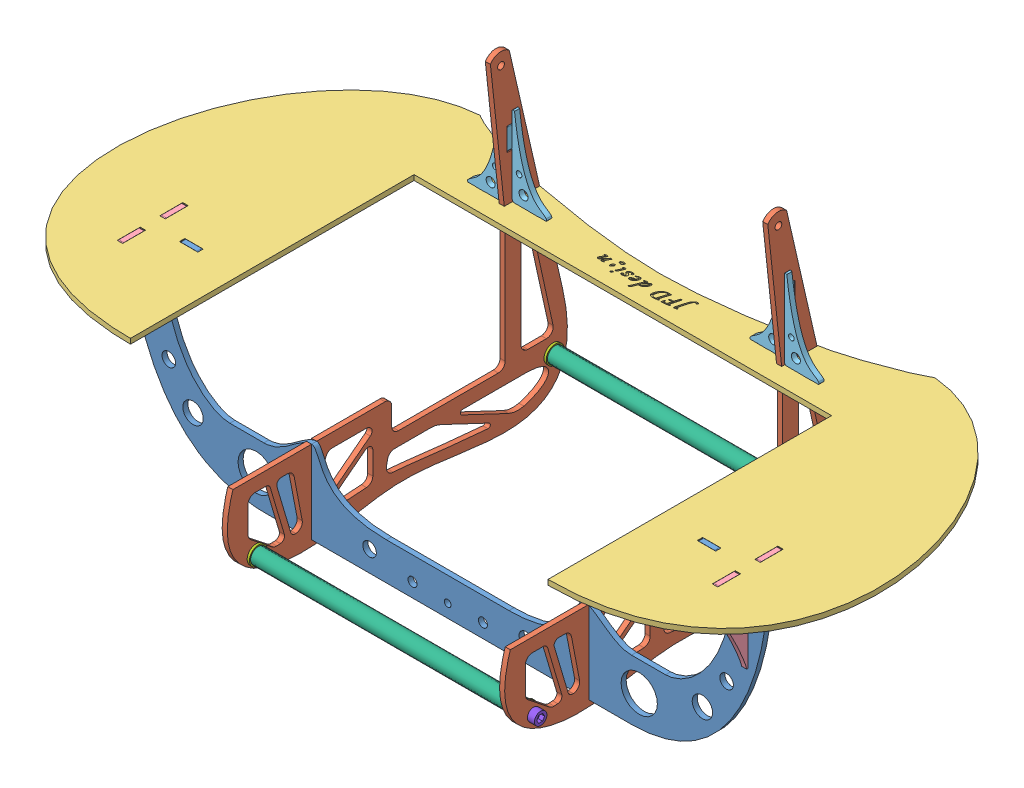
SolidWorks assembly PUPITRE2_ASM_final, configuration Default. Lengths in mm.
Overall size (343.04 155.74 164.22).
28 component instances, 8 part files, 45 mates.
Components (placement in the parent):
- TRAVERSE-1: TRAVERSE [Default] at (24.2232 -32.0952 -9.6228) size (312.1 84.77 2.25)
- FLANGE-1: FLANGE [Default] at (136.4732 -2.886 -18.3978) x (-1 0 0) z (0 0 -1) size (2.25 155.74 160.35)
- FLANGE-2: FLANGE [Default] at (14.2232 -2.886 -18.3978) x (-1 0 0) z (0 0 -1) size (2.25 155.74 160.35)
- PLATINE-2: PLATINE [Default] at (24.2232 33.9548 -84.5577) x (-1 0 0) z (0 0 -1) size (343.04 2.25 162.21)
- WEDGE1-1: WEDGE1 [Default] at (156.4732 21.4548 -8.4978) x (-1 0 0) z (0 0 -1) size (2.25 38.02 66.03)
- WEDGE1-2: WEDGE1 [Default] at (-105.7768 21.4548 -8.4978) x (-1 0 0) z (0 0 -1) size (2.25 38.02 66.03)
- WEDGE2-1: WEDGE2 [Default] at (-38.0268 36.2048 -95.8195) size (17.46 37.46 2.25)
- WEDGE2-2: WEDGE2 [Default] at (-35.7768 36.2048 -95.8195) x (-1 0 0) z (0 0 -1) size (17.46 37.46 2.25)
- WEDGE2-3: WEDGE2 [Default] at (84.2232 36.2048 -98.0695) size (17.46 37.46 2.25)
- WEDGE2-4: WEDGE2 [Default] at (86.4732 36.2048 -93.5695) x (-1 0 0) z (0 0 -1) size (17.46 37.46 2.25)
- STIFFNER-1: STIFFNER [Default] at (17.5863 -42.7957 21.3978) size (120 8 8)
  - STIFFNER-1: STIFFNER [Default] at (7.6369 0.9201 -4.3911) size (118 7 7)
  - GLUED_NUT-1: GLUED_NUT [Default] at (-53.3631 0.9201 -4.3911) x (0 -1 0) z (0 0 1) size (8 5 8)
  - GLUED_NUT-2: GLUED_NUT [Default] at (66.6369 0.9201 -4.3911) x (0 1 0) z (0 0 1) size (8 5 8)
- STIFFNER-2: STIFFNER [Default] at (17.5863 28.8847 -94.3222) size (120 8 8)
  - STIFFNER-1: STIFFNER [Default] at (7.6369 0.9201 -4.3911) size (118 7 7)
  - GLUED_NUT-1: GLUED_NUT [Default] at (-53.3631 0.9201 -4.3911) x (0 -1 0) z (0 0 1) size (8 5 8)
  - GLUED_NUT-2: GLUED_NUT [Default] at (66.6369 0.9201 -4.3911) x (0 1 0) z (0 0 1) size (8 5 8)
- STIFFNER-3: STIFFNER [Default] at (17.5863 -31.5278 -109.4197) size (120 8 8)
  - STIFFNER-1: STIFFNER [Default] at (7.6369 0.9201 -4.3911) size (118 7 7)
  - GLUED_NUT-1: GLUED_NUT [Default] at (-53.3631 0.9201 -4.3911) x (0 -1 0) z (0 0 1) size (8 5 8)
  - GLUED_NUT-2: GLUED_NUT [Default] at (66.6369 0.9201 -4.3911) x (0 1 0) z (0 0 1) size (8 5 8)
- M3_HEX_BOLT-1: M3_HEX_BOLT [Default] at (89.5732 -41.8756 17.0067) x (0 1 0) z (0 0 1) size (5.5 13.1 5.5)
- M3_HEX_BOLT-2: M3_HEX_BOLT [Default] at (-41.1268 -30.6077 -113.8109) x (0 -1 0) z (0 0 1) size (5.5 13.1 5.5)
- M3_HEX_BOLT-3: M3_HEX_BOLT [Default] at (89.5732 -30.6077 -113.8109) x (0 -0.381849 0.924225) z (0 -0.924225 -0.381849) size (5.5 13.1 5.5)
- M3_HEX_BOLT-4: M3_HEX_BOLT [Default] at (89.5732 29.8048 -98.7133) x (0 1 0) z (0 0 1) size (5.5 13.1 5.5)
- M3_HEX_BOLT-5: M3_HEX_BOLT [Default] at (-41.1268 29.8048 -98.7133) x (0 -1 0) z (0 0 1) size (5.5 13.1 5.5)
- M3_HEX_BOLT-6: M3_HEX_BOLT [Default] at (-41.1268 -41.8756 17.0067) x (0 -1 0) z (0 0 1) size (5.5 13.1 5.5)
Mates (geometry in assembly coordinates):
- Coincident1: coincident anti-aligned: plane of TRAVERSE-1 through (84.2232 -30.0952 -7.3728) normal (0 -1 0); plane of FLANGE-1 through (84.2232 -30.0952 -7.3728) normal (0 1 0)
- Coincident2: coincident anti-aligned: plane of TRAVERSE-1 through (-35.7768 -30.0952 -7.3728) normal (0 -1 0); plane of FLANGE-2 through (-38.0268 -30.0952 -7.3728) normal (0 1 0)
- Coincident4: coincident anti-aligned: plane of TRAVERSE-1 through (150.9033 -21.8485 -9.6228) normal (0 0 -1); plane of FLANGE-2 through (-38.0268 -12.0952 -9.6228) normal (0 0 1)
- Coincident6: coincident anti-aligned: plane of TRAVERSE-1 through (84.2232 -30.0952 -7.3728) normal (1 0 0); plane of FLANGE-1 through (84.2232 -46.0994 -49.779) normal (-1 0 0)
- Coincident7: coincident anti-aligned: plane of TRAVERSE-1 through (150.9033 -21.8485 -7.3728) normal (0 0 1); plane of FLANGE-1 through (84.2232 -12.0952 -7.3728) normal (0 0 -1)
- Coincident17: coincident anti-aligned: plane of TRAVERSE-1 through (-38.0268 -30.0952 -7.3728) normal (1 0 0); plane of FLANGE-2 through (-38.0268 -46.0994 -49.779) normal (-1 0 0)
- Coincident20: coincident anti-aligned: plane of TRAVERSE-1 through (156.4732 33.9548 -7.3728) normal (0 1 0); plane of PLATINE-2 through (-143.3985 33.9548 -38.7619) normal (0 -1 0)
- Coincident21: coincident anti-aligned: plane of FLANGE-1 through (84.2232 33.9048 -95.7133) normal (0 0 1); plane of PLATINE-2 through (-35.7768 36.2048 -95.7133) normal (0 0 -1)
- Coincident22: coincident anti-aligned: plane of FLANGE-1 through (86.4732 -46.0994 -49.779) normal (1 0 0); plane of PLATINE-2 through (86.4732 36.2048 -95.7133) normal (-1 0 0)
- Coincident23: coincident anti-aligned: plane of PLATINE-2 through (-143.3985 33.9548 -38.7619) normal (0 -1 0); plane of WEDGE1-1 through (154.2232 33.9548 -12.8821) normal (0 1 0)
- Coincident24: coincident anti-aligned: plane of TRAVERSE-1 through (150.9033 -21.8485 -9.6228) normal (0 0 -1); plane of WEDGE1-1 through (154.2232 16.2883 -9.6228) normal (0 0 1)
- Coincident25: coincident anti-aligned: plane of TRAVERSE-1 through (154.2232 33.9548 -7.3728) normal (1 0 0); plane of WEDGE1-1 through (154.2232 13.0847 -0.7845) normal (-1 0 0)
- Coincident26: coincident anti-aligned: plane of PLATINE-2 through (-143.3985 33.9548 -38.7619) normal (0 -1 0); plane of WEDGE1-2 through (-108.0268 33.9548 -22.8821) normal (0 1 0)
- Coincident27: coincident anti-aligned: plane of TRAVERSE-1 through (-108.0268 33.9548 -7.3728) normal (1 0 0); plane of WEDGE1-2 through (-108.0268 13.0847 -0.7845) normal (-1 0 0)
- Coincident28: coincident anti-aligned: plane of TRAVERSE-1 through (150.9033 -21.8485 -9.6228) normal (0 0 -1); plane of WEDGE1-2 through (-108.0268 16.2883 -9.6228) normal (0 0 1)
- Coincident29: coincident anti-aligned: plane of FLANGE-1 through (86.4732 -46.0994 -49.779) normal (1 0 0); plane of WEDGE2-4 through (86.4732 37.2048 -95.8195) normal (-1 0 0)
- Coincident30: coincident anti-aligned: plane of FLANGE-1 through (84.2232 -46.0994 -49.779) normal (-1 0 0); plane of WEDGE2-3 through (84.2232 37.2048 -95.8195) normal (1 0 0)
- Coincident31: coincident anti-aligned: plane of WEDGE2-3 through (75.7928 43.3043 -95.8195) normal (0 0 1); plane of WEDGE2-4 through (94.9037 43.3043 -95.8195) normal (0 0 -1)
- Coincident34: coincident anti-aligned: plane of PLATINE-2 through (-143.3985 36.2048 -38.7619) normal (0 1 0); plane of WEDGE2-4 through (87.4732 36.2048 -95.8195) normal (0 -1 0)
- Coincident35: coincident anti-aligned: plane of PLATINE-2 through (-143.3985 36.2048 -38.7619) normal (0 1 0); plane of WEDGE2-3 through (72.2232 36.2048 -95.8195) normal (0 -1 0)
- Coincident36: coincident anti-aligned: plane of FLANGE-1 through (86.4732 66.2048 -93.5695) normal (0 0 -1); plane of WEDGE2-4 through (94.9037 43.3043 -93.5695) normal (0 0 1)
- Coincident37: coincident anti-aligned: plane of WEDGE2-1 through (-46.4572 43.3043 -95.8195) normal (0 0 -1); plane of WEDGE2-2 through (-27.3463 43.3043 -95.8195) normal (0 0 1)
- Coincident38: coincident aligned: plane of WEDGE2-1 through (-39.0268 36.2048 -93.5695) normal (0 -1 0); plane of WEDGE2-2 through (-34.7768 36.2048 -98.0695) normal (0 -1 0)
- Coincident39: coincident anti-aligned: plane of FLANGE-2 through (-35.7768 66.2048 -93.5695) normal (0 0 -1); plane of WEDGE2-1 through (-46.4572 43.3043 -93.5695) normal (0 0 1)
- Coincident40: coincident anti-aligned: plane of PLATINE-2 through (-143.3985 36.2048 -38.7619) normal (0 1 0); plane of WEDGE2-1 through (-39.0268 36.2048 -93.5695) normal (0 -1 0)
- Coincident41: coincident anti-aligned: plane of FLANGE-2 through (-38.0268 -46.0994 -49.779) normal (-1 0 0); plane of WEDGE2-1 through (-38.0268 37.2048 -93.5695) normal (1 0 0)
- Coincident42: coincident anti-aligned: plane of FLANGE-2 through (-35.7768 -46.0994 -49.779) normal (1 0 0); plane of WEDGE2-2 through (-35.7768 66.2048 -98.0695) normal (-1 0 0)
- Concentric1: concentric aligned: cylinder of FLANGE-1 through (84.2232 29.8048 -98.7133) axis (1 0 0) radius 1.525; cylinder of STIFFNER-2/GLUED_NUT-2 through (83.2232 29.8048 -98.7133) axis (1 0 0) radius 1.5
- Coincident43: coincident anti-aligned: plane of FLANGE-1 through (84.2232 -46.0994 -49.779) normal (-1 0 0); plane of STIFFNER-2/GLUED_NUT-2 through (84.2232 29.8048 -98.7133) normal (1 0 0)
- Coincident44: coincident anti-aligned: plane of FLANGE-2 through (-35.7768 -46.0994 -49.779) normal (1 0 0); plane of STIFFNER-3/GLUED_NUT-1 through (-35.7768 -30.6077 -113.8109) normal (-1 0 0)
- Coincident45: coincident anti-aligned: plane of FLANGE-2 through (-35.7768 -46.0994 -49.779) normal (1 0 0); plane of STIFFNER-1/GLUED_NUT-1 through (-35.7768 -41.8756 17.0067) normal (-1 0 0)
- Concentric2: concentric aligned: cylinder of FLANGE-1 through (84.2232 -30.6077 -113.8109) axis (1 0 0) radius 1.525; cylinder of STIFFNER-3/GLUED_NUT-2 through (83.2232 -30.6077 -113.8109) axis (1 0 0) radius 1.5
- Concentric3: concentric aligned: cylinder of FLANGE-1 through (84.2232 -41.8756 17.0067) axis (1 0 0) radius 1.525; cylinder of STIFFNER-1/GLUED_NUT-2 through (83.2232 -41.8756 17.0067) axis (1 0 0) radius 1.5
- Concentric5: concentric anti-aligned: cylinder of FLANGE-2 through (-38.0268 29.8048 -98.7133) axis (1 0 0) radius 1.525; cylinder of M3_HEX_BOLT-5 through (-28.0268 29.8048 -98.7133) axis (-1 0 0) radius 1.5
- Concentric6: concentric anti-aligned: cylinder of FLANGE-2 through (-38.0268 -30.6077 -113.8109) axis (1 0 0) radius 1.525; cylinder of M3_HEX_BOLT-2 through (-28.0268 -30.6077 -113.8109) axis (-1 0 0) radius 1.5
- Concentric7: concentric anti-aligned: cylinder of FLANGE-2 through (-38.0268 -41.8756 17.0067) axis (1 0 0) radius 1.525; cylinder of M3_HEX_BOLT-6 through (-28.0268 -41.8756 17.0067) axis (-1 0 0) radius 1.5
- Coincident47: coincident anti-aligned: plane of FLANGE-2 through (-38.0268 -46.0994 -49.779) normal (-1 0 0); plane of M3_HEX_BOLT-6 through (-38.0268 -41.8756 17.0067) normal (1 0 0)
- Coincident48: coincident anti-aligned: plane of FLANGE-2 through (-38.0268 -46.0994 -49.779) normal (-1 0 0); plane of M3_HEX_BOLT-2 through (-38.0268 -30.6077 -113.8109) normal (1 0 0)
- Coincident49: coincident anti-aligned: plane of FLANGE-2 through (-38.0268 -46.0994 -49.779) normal (-1 0 0); plane of M3_HEX_BOLT-5 through (-38.0268 29.8048 -98.7133) normal (1 0 0)
- Concentric8: concentric aligned: cylinder of FLANGE-1 through (84.2232 -30.6077 -113.8109) axis (1 0 0) radius 1.525; cylinder of M3_HEX_BOLT-3 through (76.4732 -30.6077 -113.8109) axis (1 0 0) radius 1.5
- Concentric9: concentric aligned: cylinder of FLANGE-1 through (84.2232 29.8048 -98.7133) axis (1 0 0) radius 1.525; cylinder of M3_HEX_BOLT-4 through (76.4732 29.8048 -98.7133) axis (1 0 0) radius 1.5
- Concentric10: concentric aligned: cylinder of FLANGE-1 through (84.2232 -41.8756 17.0067) axis (1 0 0) radius 1.525; cylinder of M3_HEX_BOLT-1 through (76.4732 -41.8756 17.0067) axis (1 0 0) radius 1.5
- Coincident50: coincident anti-aligned: plane of FLANGE-1 through (86.4732 -46.0994 -49.779) normal (1 0 0); plane of M3_HEX_BOLT-1 through (86.4732 -41.8756 17.0067) normal (-1 0 0)
- Coincident51: coincident anti-aligned: plane of FLANGE-1 through (86.4732 -46.0994 -49.779) normal (1 0 0); plane of M3_HEX_BOLT-4 through (86.4732 29.8048 -98.7133) normal (-1 0 0)
- Coincident52: coincident anti-aligned: plane of FLANGE-1 through (86.4732 -46.0994 -49.779) normal (1 0 0); plane of M3_HEX_BOLT-3 through (86.4732 -30.6077 -113.8109) normal (-1 0 0)
